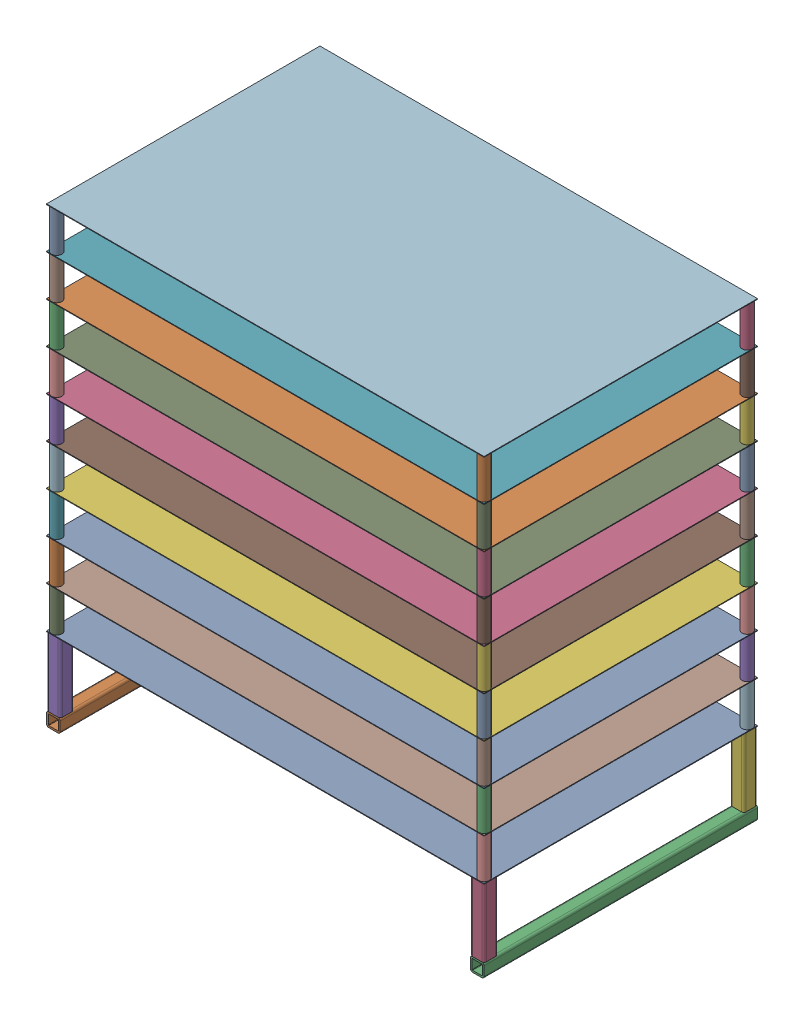
SolidWorks assembly Stacked Tray Assembly, configuration Default. Lengths in mm.
Overall size (406.4 420.32 254).
62 component instances, 4 part files, 3 mates.
Components (placement in the parent):
- Bottom Tray Assembly-1: Bottom Tray Assembly [Default] at (173.9076 -76.6729 -13.7937) size (406.4 76.81 254)
  - Perforated Tray-1: Perforated Tray [92725T36] at (-209.6714 56.3674 72.3455) size (406.4 0.61 254)
  - Tray Base-1: Tray Base [89825K319] at (-406.5214 -13.7874 72.3455) size (12.7 12.7 254)
  - Tray Base-2: Tray Base [89825K319] at (-12.8214 -13.7874 72.3455) size (12.7 12.7 254)
  - Tray Sides-1: Tray Sides [89825K319] at (-12.8214 24.3126 192.9955) x (1 0 0) z (0 -1 0) size (12.7 12.7 63.5)
  - Tray Sides-2: Tray Sides [89825K319] at (-406.5214 24.3126 192.9955) x (1 0 0) z (0 -1 0) size (12.7 12.7 63.5)
  - Tray Sides-3: Tray Sides [89825K319] at (-12.8214 24.3126 -48.3045) x (1 0 0) z (0 -1 0) size (12.7 12.7 63.5)
  - Tray Sides-4: Tray Sides [89825K319] at (-406.5214 24.3126 -48.3045) x (1 0 0) z (0 -1 0) size (12.7 12.7 63.5)
- Additional Tray Assembly-1: Additional Tray Assembly [Default] at (65.2935 16.9544 6.2103) size (406.4 38.71 254)
  - Perforated Tray-1: Perforated Tray [92725T36] at (-101.0573 1.4498 52.3416) size (406.4 0.61 254)
  - Additional Tray Legs-1: Additional Tray Legs [8457K25] at (-299.4948 -17.905 174.5791) x (1 0 0) z (0 1 0) size (9.53 9.53 38.1)
  - Additional Tray Legs-2: Additional Tray Legs [8457K25] at (97.3802 -17.905 174.5791) x (1 0 0) z (0 1 0) size (9.53 9.53 38.1)
  - Additional Tray Legs-3: Additional Tray Legs [8457K25] at (-299.4948 -17.905 -69.8959) x (1 0 0) z (0 1 0) size (9.53 9.53 38.1)
  - Additional Tray Legs-4: Additional Tray Legs [8457K25] at (97.3802 -17.905 -69.8959) x (1 0 0) z (0 1 0) size (9.53 9.53 38.1)
- Additional Tray Assembly-7: Additional Tray Assembly [Default] at (65.2935 55.0544 6.2103) size (406.4 38.71 254)
  - Perforated Tray-1: Perforated Tray [92725T36] at (-101.0573 1.4498 52.3416) size (406.4 0.61 254)
  - Additional Tray Legs-1: Additional Tray Legs [8457K25] at (-299.4948 -17.905 174.5791) x (1 0 0) z (0 1 0) size (9.53 9.53 38.1)
  - Additional Tray Legs-2: Additional Tray Legs [8457K25] at (97.3802 -17.905 174.5791) x (1 0 0) z (0 1 0) size (9.53 9.53 38.1)
  - Additional Tray Legs-3: Additional Tray Legs [8457K25] at (-299.4948 -17.905 -69.8959) x (1 0 0) z (0 1 0) size (9.53 9.53 38.1)
  - Additional Tray Legs-4: Additional Tray Legs [8457K25] at (97.3802 -17.905 -69.8959) x (1 0 0) z (0 1 0) size (9.53 9.53 38.1)
- Additional Tray Assembly-8: Additional Tray Assembly [Default] at (65.2935 93.1544 6.2103) size (406.4 38.71 254)
  - Perforated Tray-1: Perforated Tray [92725T36] at (-101.0573 1.4498 52.3416) size (406.4 0.61 254)
  - Additional Tray Legs-1: Additional Tray Legs [8457K25] at (-299.4948 -17.905 174.5791) x (1 0 0) z (0 1 0) size (9.53 9.53 38.1)
  - Additional Tray Legs-2: Additional Tray Legs [8457K25] at (97.3802 -17.905 174.5791) x (1 0 0) z (0 1 0) size (9.53 9.53 38.1)
  - Additional Tray Legs-3: Additional Tray Legs [8457K25] at (-299.4948 -17.905 -69.8959) x (1 0 0) z (0 1 0) size (9.53 9.53 38.1)
  - Additional Tray Legs-4: Additional Tray Legs [8457K25] at (97.3802 -17.905 -69.8959) x (1 0 0) z (0 1 0) size (9.53 9.53 38.1)
- Additional Tray Assembly-9: Additional Tray Assembly [Default] at (65.2935 131.2544 6.2103) size (406.4 38.71 254)
  - Perforated Tray-1: Perforated Tray [92725T36] at (-101.0573 1.4498 52.3416) size (406.4 0.61 254)
  - Additional Tray Legs-1: Additional Tray Legs [8457K25] at (-299.4948 -17.905 174.5791) x (1 0 0) z (0 1 0) size (9.53 9.53 38.1)
  - Additional Tray Legs-2: Additional Tray Legs [8457K25] at (97.3802 -17.905 174.5791) x (1 0 0) z (0 1 0) size (9.53 9.53 38.1)
  - Additional Tray Legs-3: Additional Tray Legs [8457K25] at (-299.4948 -17.905 -69.8959) x (1 0 0) z (0 1 0) size (9.53 9.53 38.1)
  - Additional Tray Legs-4: Additional Tray Legs [8457K25] at (97.3802 -17.905 -69.8959) x (1 0 0) z (0 1 0) size (9.53 9.53 38.1)
- Additional Tray Assembly-10: Additional Tray Assembly [Default] at (65.2935 169.3544 6.2103) size (406.4 38.71 254)
  - Perforated Tray-1: Perforated Tray [92725T36] at (-101.0573 1.4498 52.3416) size (406.4 0.61 254)
  - Additional Tray Legs-1: Additional Tray Legs [8457K25] at (-299.4948 -17.905 174.5791) x (1 0 0) z (0 1 0) size (9.53 9.53 38.1)
  - Additional Tray Legs-2: Additional Tray Legs [8457K25] at (97.3802 -17.905 174.5791) x (1 0 0) z (0 1 0) size (9.53 9.53 38.1)
  - Additional Tray Legs-3: Additional Tray Legs [8457K25] at (-299.4948 -17.905 -69.8959) x (1 0 0) z (0 1 0) size (9.53 9.53 38.1)
  - Additional Tray Legs-4: Additional Tray Legs [8457K25] at (97.3802 -17.905 -69.8959) x (1 0 0) z (0 1 0) size (9.53 9.53 38.1)
- Additional Tray Assembly-11: Additional Tray Assembly [Default] at (65.2935 207.4544 6.2103) size (406.4 38.71 254)
  - Perforated Tray-1: Perforated Tray [92725T36] at (-101.0573 1.4498 52.3416) size (406.4 0.61 254)
  - Additional Tray Legs-1: Additional Tray Legs [8457K25] at (-299.4948 -17.905 174.5791) x (1 0 0) z (0 1 0) size (9.53 9.53 38.1)
  - Additional Tray Legs-2: Additional Tray Legs [8457K25] at (97.3802 -17.905 174.5791) x (1 0 0) z (0 1 0) size (9.53 9.53 38.1)
  - Additional Tray Legs-3: Additional Tray Legs [8457K25] at (-299.4948 -17.905 -69.8959) x (1 0 0) z (0 1 0) size (9.53 9.53 38.1)
  - Additional Tray Legs-4: Additional Tray Legs [8457K25] at (97.3802 -17.905 -69.8959) x (1 0 0) z (0 1 0) size (9.53 9.53 38.1)
- Additional Tray Assembly-12: Additional Tray Assembly [Default] at (65.2935 245.5544 6.2103) size (406.4 38.71 254)
  - Perforated Tray-1: Perforated Tray [92725T36] at (-101.0573 1.4498 52.3416) size (406.4 0.61 254)
  - Additional Tray Legs-1: Additional Tray Legs [8457K25] at (-299.4948 -17.905 174.5791) x (1 0 0) z (0 1 0) size (9.53 9.53 38.1)
  - Additional Tray Legs-2: Additional Tray Legs [8457K25] at (97.3802 -17.905 174.5791) x (1 0 0) z (0 1 0) size (9.53 9.53 38.1)
  - Additional Tray Legs-3: Additional Tray Legs [8457K25] at (-299.4948 -17.905 -69.8959) x (1 0 0) z (0 1 0) size (9.53 9.53 38.1)
  - Additional Tray Legs-4: Additional Tray Legs [8457K25] at (97.3802 -17.905 -69.8959) x (1 0 0) z (0 1 0) size (9.53 9.53 38.1)
- Additional Tray Assembly-13: Additional Tray Assembly [Default] at (65.2935 283.6544 6.2103) size (406.4 38.71 254)
  - Perforated Tray-1: Perforated Tray [92725T36] at (-101.0573 1.4498 52.3416) size (406.4 0.61 254)
  - Additional Tray Legs-1: Additional Tray Legs [8457K25] at (-299.4948 -17.905 174.5791) x (1 0 0) z (0 1 0) size (9.53 9.53 38.1)
  - Additional Tray Legs-2: Additional Tray Legs [8457K25] at (97.3802 -17.905 174.5791) x (1 0 0) z (0 1 0) size (9.53 9.53 38.1)
  - Additional Tray Legs-3: Additional Tray Legs [8457K25] at (-299.4948 -17.905 -69.8959) x (1 0 0) z (0 1 0) size (9.53 9.53 38.1)
  - Additional Tray Legs-4: Additional Tray Legs [8457K25] at (97.3802 -17.905 -69.8959) x (1 0 0) z (0 1 0) size (9.53 9.53 38.1)
- Additional Tray Assembly-14: Additional Tray Assembly [Default] at (65.2935 321.7544 6.2103) size (406.4 38.71 254)
  - Perforated Tray-1: Perforated Tray [92725T36] at (-101.0573 1.4498 52.3416) size (406.4 0.61 254)
  - Additional Tray Legs-1: Additional Tray Legs [8457K25] at (-299.4948 -17.905 174.5791) x (1 0 0) z (0 1 0) size (9.53 9.53 38.1)
  - Additional Tray Legs-2: Additional Tray Legs [8457K25] at (97.3802 -17.905 174.5791) x (1 0 0) z (0 1 0) size (9.53 9.53 38.1)
  - Additional Tray Legs-3: Additional Tray Legs [8457K25] at (-299.4948 -17.905 -69.8959) x (1 0 0) z (0 1 0) size (9.53 9.53 38.1)
  - Additional Tray Legs-4: Additional Tray Legs [8457K25] at (97.3802 -17.905 -69.8959) x (1 0 0) z (0 1 0) size (9.53 9.53 38.1)
Mates (geometry in assembly coordinates):
- Coincident1: coincident anti-aligned: plane of Bottom Tray Assembly-1/Perforated Tray-1 through (-238.9638 -20.0006 185.5519) normal (0 1 0); plane of Additional Tray Assembly-1/Additional Tray Legs-2 through (162.6737 -20.0006 180.7894) normal (0 -1 0)
- Coincident2: coincident aligned: plane of Bottom Tray Assembly-1/Perforated Tray-1 through (-35.7638 -20.3054 185.5519) normal (0 0 1); plane of Additional Tray Assembly-1/Perforated Tray-1 through (-35.7638 18.4042 185.5519) normal (0 0 1)
- Coincident3: coincident aligned: plane of Bottom Tray Assembly-1/Perforated Tray-1 through (167.4362 -20.6102 185.5519) normal (1 0 0); plane of Additional Tray Assembly-1/Perforated Tray-1 through (167.4362 18.0994 185.5519) normal (1 0 0)
